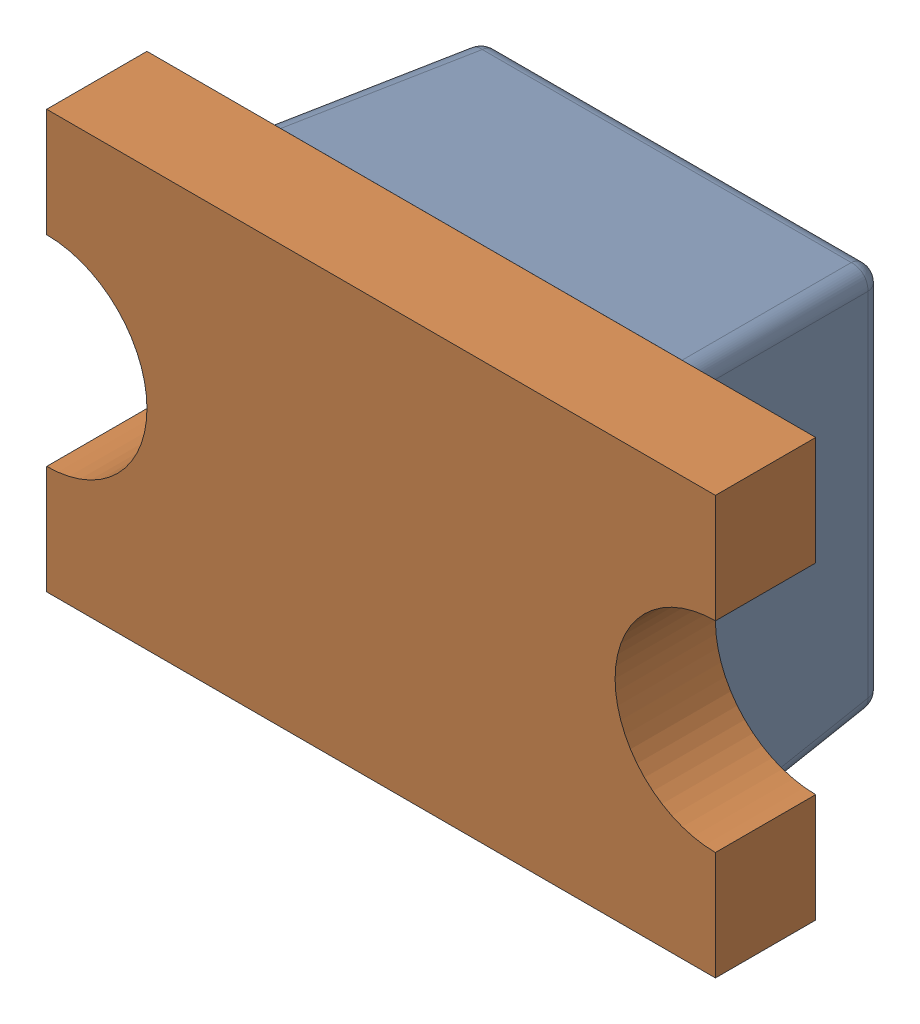
SolidWorks assembly D8_2, configuration Default. Lengths in mm.
Overall size (2 1.25 0.9).
2 component instances, 2 part files, 0 mates.
Components (placement in the parent):
- LED 0805 Lens RED-1: LED 0805 Lens RED [Default] at (108.8309 95.663 -1.2114) x (-1 0 0) z (0 -1 0) size (1.3 0.6 1.25)
- LED 0805 Base RED-1: LED 0805 Base RED [Default] at (108.8309 95.663 -1.2114) x (-1 0 0) z (0 -1 0) size (2 0.4 1.25)
